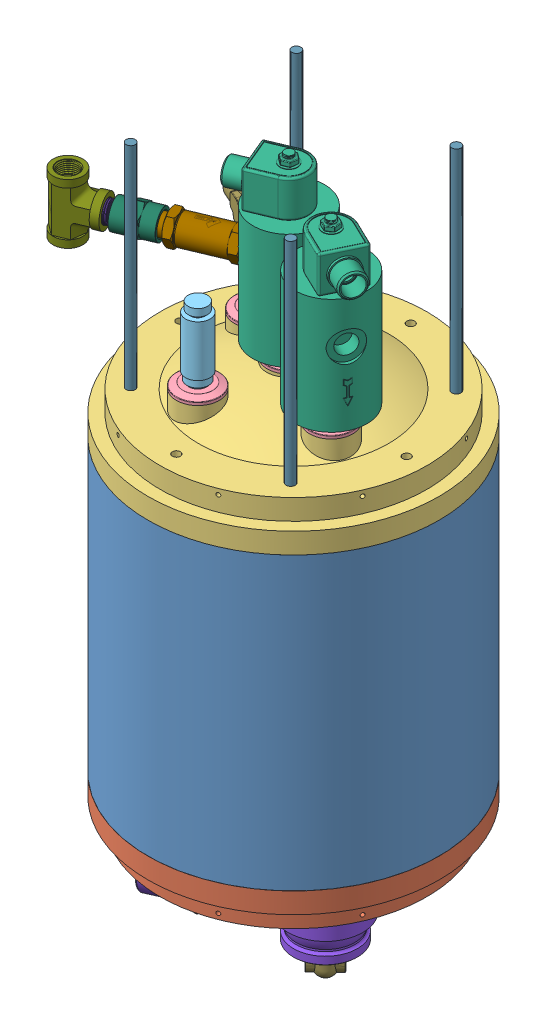
SolidWorks assembly 000053-R02_LOX_TANK_ASSM, configuration Default. Lengths in mm.
Overall size (408.23 765.71 408.23).
29 component instances, 17 part files, 50 mates.
Components (placement in the parent):
- 000055-R02_LOX_TANK_WALL-1: 000055-R02_LOX_TANK_WALL [Default] at (0 -152.4 0) x (0.896707 0 0.442625) z (-0.442625 0 0.896707) size (304.8 304.8 304.8)
- 000052-R02b_TANK_BULKHEAD_BOTTOM-2: 000052-R02b_TANK_BULKHEAD_BOTTOM [Default] at (0 -152.4 0) x (-0.398871 0 0.917007) z (0.917007 0 0.398871) size (304.8 66.04 304.8)
- 000052-R02a_TANK_BULKHEAD_TOP-1: 000052-R02a_TANK_BULKHEAD_TOP [Default] at (0 152.4 0) x (-0.917007 0 -0.398871) z (0.398871 0 -0.917007) size (304.8 66.04 304.8)
- FUELTANKPARTS-1-2-AL-FITTING-3: FUELTANKPARTS-1-2-AL-FITTING [Default] at (-69.8759 209.042 -30.394) x (0.997228 0 0.074408) z (-0.074408 0 0.997228) size (44.96 12.45 44.96)
- FUELTANKPARTS-1-2-AL-FITTING-4: FUELTANKPARTS-1-2-AL-FITTING [Default] at (-8.7345 211.582 -3.7993) x (0.985124 0 -0.171846) z (0.171846 0 0.985124) size (44.96 12.45 44.96)
- FUELTANKPARTS-1-2-AL-FITTING-9: FUELTANKPARTS-1-2-AL-FITTING [Default] at (-30.394 -209.042 69.8759) x (-0.381098 0 -0.924535) z (-0.924535 0 0.381098) size (44.96 12.45 44.96)
- FUELTANKPARTS-1-2-AL-FITTING-10: FUELTANKPARTS-1-2-AL-FITTING [Default] at (10.1313 -211.582 -23.292) x (-0.381098 0 -0.924535) z (-0.924535 0 0.381098) size (44.96 12.45 44.96)
- FUELTANKPARTS-1-2-AL-FITTING-12: FUELTANKPARTS-1-2-AL-FITTING [Default] at (-30.394 209.042 69.8759) x (0.074408 0 -0.997228) z (0.997228 0 0.074408) size (44.96 12.45 44.96)
- FUELTANKPARTS-1-2-AL-FITTING-13: FUELTANKPARTS-1-2-AL-FITTING [Default] at (69.8759 209.042 30.394) x (-0.997228 0 -0.074408) z (0.074408 0 -0.997228) size (44.96 12.45 44.96)
- cryo-pducer-temp-1: cryo-pducer-temp [Default] at (-30.394 211.328 69.8759) size (25.65 83.82 25.65)
- EH50-08-D024-OXXP-1: EH50-08-D024-OXXP [Default] at (-8.7345 311.3278 -3.7993) x (-0.922505 0 0.385985) z (-0.385985 0 -0.922505) size (87.5 168.84 74.93)
- CRVP4-500B-1: CRVP4-500B [Default] at (-69.8759 209.042 -30.394) x (0 1 0) z (0 0 1) size (82.27 25.15 25.15)
- atomatik-2: atomatik [Default] at (10.1313 -265.7517 -23.292) x (0 -1 0) z (-0.405568 0 -0.914065) size (76.23 180.98 78)
- TIN20021-1: TIN20021 [Default] at (-97.1889 311.3278 33.2109) x (0.922505 0 -0.385985) z (-0.385985 0 -0.922505) size (102.11 28.58 33)
- 44665K173_STANDARD-WALL ALUMINUM THREADED PIPE NIPPLE-1: 44665K173_STANDARD-WALL ALUMINUM THREADED PIPE NIPPLE [44665K173] at (69.8759 227.0379 30.394) x (-0.099238 0 -0.995064) z (0 1 0) size (22.19 22.36 51.97)
- 44665K173_STANDARD-WALL ALUMINUM THREADED PIPE NIPPLE-2: 44665K173_STANDARD-WALL ALUMINUM THREADED PIPE NIPPLE [44665K173] at (-8.7345 229.5779 -3.7993) x (0.19121 0 -0.981549) z (0 1 0) size (22.19 22.36 51.97)
- 44665K173_STANDARD-WALL ALUMINUM THREADED PIPE NIPPLE-3: 44665K173_STANDARD-WALL ALUMINUM THREADED PIPE NIPPLE [44665K173] at (10.1313 -229.5779 -23.292) x (-0.147711 0 -0.989031) z (0 1 0) size (22.19 22.36 51.97)
- 48805K184_PRECISION EXTREME-PRESSURE 316SS PIPE FITTING-1: 48805K184_PRECISION EXTREME-PRESSURE 316SS PIPE FITTING [48805K184] at (-30.394 -234.188 69.8759) x (0 -1 0) z (-0.983195 0 -0.182556) size (48.72 34.63 25.66)
- 3861T240_MED-PRESSURE ANODIZED ALUM THRD PIPE FITTING-2: 3861T240_MED-PRESSURE ANODIZED ALUM THRD PIPE FITTING [3861T24] at (-10.4238 -332.3821 -44.8205) x (-0.723269 0 0.690566) z (-0.690566 0 -0.723269) size (30.97 56.51 41.63)
- MCMASTER_94435A523_5in-5: MCMASTER_94435A523_5in [Default] at (-120.6313 -316.23 -2.1217) x (0 1 0) z (-0.995572 0 -0.094007) size (127 9.53 9.53)
- MCMASTER_94435A523_9in-5: MCMASTER_94435A523_9in [Default] at (-86.7995 189.23 83.799) x (0 1 0) z (-0.951783 0 0.306771) size (228.6 9.53 9.53)
- MCMASTER_94435A523_9in-6: MCMASTER_94435A523_9in [Default] at (83.799 189.23 86.7995) x (0 1 0) z (0.306771 0 0.951783) size (228.6 9.53 9.53)
- MCMASTER_94435A523_9in-7: MCMASTER_94435A523_9in [Default] at (86.7995 189.23 -83.799) x (0 1 0) z (0.951783 0 -0.306771) size (228.6 9.53 9.53)
- MCMASTER_94435A523_9in-8: MCMASTER_94435A523_9in [Default] at (-83.799 189.23 -86.7995) x (0 1 0) z (-0.306771 0 -0.951783) size (228.6 9.53 9.53)
- 3861T240_MED-PRESSURE ANODIZED ALUM THRD PIPE FITTING-3: 3861T240_MED-PRESSURE ANODIZED ALUM THRD PIPE FITTING [3861T24] at (-97.0429 312.3406 -42.5575) x (0.408641 0 -0.912695) z (-0.912695 0 -0.408641) size (30.97 56.51 41.63)
- 51205K223_EXTREME-PRESSURE 316 SS THREADED PIPE FITTING-1: 51205K223_EXTREME-PRESSURE 316 SS THREADED PIPE FITTING [51205K223] at (-119.4489 311.3278 42.5247) x (-0.385985 0 -0.922505) z (-0.922505 0 0.385985) size (28.7 32.74 38.1)
- 51205K245_EXTREME-PRESSURE 316 SS THREADED PIPE FITTING-1: 51205K245_EXTREME-PRESSURE 316 SS THREADED PIPE FITTING [51205K245] at (-171.8921 311.3278 64.4675) x (0 -1 0) z (0.385985 0 0.922505) size (63.86 47.51 31.16)
- 44665K211_STANDARD-WALL ALUMINUM THREADED PIPE NIPPLE-1: 44665K211_STANDARD-WALL ALUMINUM THREADED PIPE NIPPLE [44665K211] at (-142.1776 311.3278 52.0346) x (0.36865 0.296317 0.881075) z (-0.922505 0 0.385985) size (21.92 21.87 39.26)
- EH50-08-D024-OXXP-2: EH50-08-D024-OXXP [Default] at (69.8759 308.7878 30.394) x (0.900951 0 0.43392) z (-0.43392 0 0.900951) size (87.5 168.84 74.93)
Mates (geometry in assembly coordinates):
- Coincident1: coincident anti-aligned: line of 000055-R02_LOX_TANK_WALL-1 through (304.8 0 58.4669) axis (0 0 -1); line of 000052-R02a_TANK_BULKHEAD_TOP-1 through (0 102.5587 0) axis (0 1 0)
- Coincident2: coincident aligned: line of 000055-R02_LOX_TANK_WALL-1 through (304.8 0 58.4669) axis (0 0 -1); line of 000052-R02b_TANK_BULKHEAD_BOTTOM-2 through (0 -246.3331 0) axis (0 -1 0)
- Coincident4: coincident anti-aligned: plane of 000055-R02_LOX_TANK_WALL-1 through (0 -246.3331 0) normal (0 -1 0); plane of 000052-R02b_TANK_BULKHEAD_BOTTOM-2 through (-58.2552 -246.3331 133.9289) normal (0 1 0)
- Coincident7: coincident anti-aligned: plane of 000052-R02a_TANK_BULKHEAD_TOP-1 through (-8.7345 218.44 -3.7993) normal (0 1 0); plane of FUELTANKPARTS-1-2-AL-FITTING-4 through (-8.7345 218.44 -3.7993) normal (0 -1 0)
- Coincident9: coincident anti-aligned: plane of 000052-R02b_TANK_BULKHEAD_BOTTOM-2 through (-30.394 -309.8331 69.8759) normal (0 -1 0); plane of FUELTANKPARTS-1-2-AL-FITTING-9 through (-30.394 -309.8331 69.8759) normal (0 1 0)
- Concentric8: concentric anti-aligned: cylinder of 000052-R02b_TANK_BULKHEAD_BOTTOM-2 through (-30.394 -309.8331 69.8759) axis (0 -1 0) radius 12.7; cylinder of FUELTANKPARTS-1-2-AL-FITTING-9 through (-30.394 -309.8331 69.8759) axis (0 1 0) radius 12.7
- Coincident10: coincident anti-aligned: plane of 000052-R02b_TANK_BULKHEAD_BOTTOM-2 through (10.1313 -312.3731 -23.292) normal (0 -1 0); plane of FUELTANKPARTS-1-2-AL-FITTING-10 through (10.1313 -312.3731 -23.292) normal (0 1 0)
- Concentric9: concentric anti-aligned: cylinder of 000052-R02b_TANK_BULKHEAD_BOTTOM-2 through (10.1313 -312.3731 -23.292) axis (0 -1 0) radius 12.7; cylinder of FUELTANKPARTS-1-2-AL-FITTING-10 through (10.1313 -312.3731 -23.292) axis (0 1 0) radius 12.7
- Concentric10: concentric anti-aligned: cylinder of 000052-R02a_TANK_BULKHEAD_TOP-1 through (-69.8759 215.9 -30.394) axis (0 1 0) radius 12.7; cylinder of FUELTANKPARTS-1-2-AL-FITTING-3 through (-69.8759 215.9 -30.394) axis (0 -1 0) radius 12.7
- Coincident13: coincident anti-aligned: plane of 000052-R02a_TANK_BULKHEAD_TOP-1 through (-69.8759 215.9 -30.394) normal (0 1 0); plane of FUELTANKPARTS-1-2-AL-FITTING-3 through (-69.8759 215.9 -30.394) normal (0 -1 0)
- Concentric12: concentric anti-aligned: cylinder of FUELTANKPARTS-1-2-AL-FITTING-9 through (-30.394 -315.4211 69.8759) axis (0 1 0) radius 9.271; cylinder of FUELTANKPARTS-1-2-AL-FITTING-12 through (-30.394 221.488 69.8759) axis (0 -1 0) radius 9.271
- Concentric13: concentric aligned: cylinder of FUELTANKPARTS-1-2-AL-FITTING-12 through (-30.394 221.488 69.8759) axis (0 -1 0) radius 9.271; cylinder of cryo-pducer-temp-1 through (-30.394 211.328 69.8759) axis (0 -1 0) radius 8.89
- Distance2: distance = 2.54 mm anti-aligned: plane of cryo-pducer-temp-1 through (-18.964 224.028 69.8759) normal (0 -1 0); plane of FUELTANKPARTS-1-2-AL-FITTING-12 through (-30.394 221.488 69.8759) normal (0 1 0)
- Concentric14: concentric anti-aligned: cylinder of FUELTANKPARTS-1-2-AL-FITTING-4 through (-8.7345 224.028 -3.7993) axis (0 -1 0) radius 9.271; cone of EH50-08-D024-OXXP-1 through (-8.7345 235.1278 -3.7993) axis (0 1 0)
- Concentric16: concentric anti-aligned: cylinder of 000052-R02a_TANK_BULKHEAD_TOP-1 through (-8.7345 218.44 -3.7993) axis (0 1 0) radius 12.7; cylinder of FUELTANKPARTS-1-2-AL-FITTING-4 through (-8.7345 218.44 -3.7993) axis (0 -1 0) radius 12.7
- Concentric19: concentric aligned: cylinder of FUELTANKPARTS-1-2-AL-FITTING-3 through (-69.8759 221.488 -30.394) axis (0 -1 0) radius 9.271; cone of CRVP4-500B-1 through (-69.8759 224.028 -30.394) axis (0 -1 0)
- Distance5: distance = 2.54 mm anti-aligned: plane of CRVP4-500B-1 through (-69.8759 224.028 -30.394) normal (0 -1 0); plane of FUELTANKPARTS-1-2-AL-FITTING-3 through (-69.8759 221.488 -30.394) normal (0 1 0)
- Concentric22: concentric aligned: cone of EH50-08-D024-OXXP-1 through (-40.0157 311.3278 9.2891) axis (0.922505 0 -0.385985); cone of TIN20021-1 through (-38.6977 311.3278 8.7376) axis (0.922505 0 -0.385985)
- Coincident26: coincident anti-aligned: plane of EH50-08-D024-OXXP-1; plane of TIN20021-1
- Concentric32: concentric anti-aligned: cylinder of FUELTANKPARTS-1-2-AL-FITTING-13 through (69.8759 221.488 30.394) axis (0 -1 0) radius 9.271; cylinder of 44665K173_STANDARD-WALL ALUMINUM THREADED PIPE NIPPLE-1 through (69.8759 221.488 30.394) axis (0 1 0) radius 10.668
- Coincident35: coincident aligned: plane of FUELTANKPARTS-1-2-AL-FITTING-13 through (69.8759 221.488 30.394) normal (0 1 0); circle of 44665K173_STANDARD-WALL ALUMINUM THREADED PIPE NIPPLE-1
- Concentric34: concentric anti-aligned: cylinder of FUELTANKPARTS-1-2-AL-FITTING-4 through (-8.7345 224.028 -3.7993) axis (0 -1 0) radius 9.271; cylinder of 44665K173_STANDARD-WALL ALUMINUM THREADED PIPE NIPPLE-2 through (-8.7345 224.028 -3.7993) axis (0 1 0) radius 10.668
- Coincident37: coincident aligned: plane of EH50-08-D024-OXXP-1 through (-11.6634 235.1278 -2.5737) normal (0 -1 0); circle of 44665K173_STANDARD-WALL ALUMINUM THREADED PIPE NIPPLE-2
- Coincident38: coincident aligned: plane of FUELTANKPARTS-1-2-AL-FITTING-4 through (-8.7345 224.028 -3.7993) normal (0 1 0); circle of 44665K173_STANDARD-WALL ALUMINUM THREADED PIPE NIPPLE-2
- Concentric35: concentric aligned: cylinder of atomatik-2 through (10.1313 -384.3156 -23.292) axis (0 1 0) radius 16.775; cylinder of 44665K173_STANDARD-WALL ALUMINUM THREADED PIPE NIPPLE-3 through (10.1313 -329.0609 -23.292) axis (0 1 0) radius 10.668
- Concentric36: concentric aligned: cylinder of FUELTANKPARTS-1-2-AL-FITTING-10 through (10.1313 -317.9611 -23.292) axis (0 1 0) radius 9.271; cylinder of 44665K173_STANDARD-WALL ALUMINUM THREADED PIPE NIPPLE-3 through (10.1313 -329.0609 -23.292) axis (0 1 0) radius 10.668
- Coincident39: coincident aligned: plane of FUELTANKPARTS-1-2-AL-FITTING-10 through (10.1313 -317.9611 -23.292) normal (0 -1 0); circle of 44665K173_STANDARD-WALL ALUMINUM THREADED PIPE NIPPLE-3
- Coincident40: coincident aligned: plane of atomatik-2 through (25.4648 -329.0609 -30.0954) normal (0 1 0); circle of 44665K173_STANDARD-WALL ALUMINUM THREADED PIPE NIPPLE-3
- Concentric37: concentric aligned: cylinder of FUELTANKPARTS-1-2-AL-FITTING-9 through (-30.394 -315.4211 69.8759) axis (0 1 0) radius 9.271; cylinder of 48805K184_PRECISION EXTREME-PRESSURE 316SS PIPE FITTING-1 through (-30.394 -328.1211 69.8759) axis (0 1 0) radius 5.207
- Coincident41: coincident anti-aligned: plane of FUELTANKPARTS-1-2-AL-FITTING-9 through (-30.394 -315.4211 69.8759) normal (0 -1 0); plane of 48805K184_PRECISION EXTREME-PRESSURE 316SS PIPE FITTING-1 through (-52.2455 -315.4211 65.8186) normal (0 1 0)
- Concentric38: concentric aligned: cylinder of atomatik-2 through (10.1313 -384.3156 -23.292) axis (0 1 0) radius 16.775; cylinder of 3861T240_MED-PRESSURE ANODIZED ALUM THRD PIPE FITTING-2 through (10.1313 -408.4558 -23.292) axis (0 1 0) radius 6.7469
- Coincident42: coincident anti-aligned: plane of atomatik-2 through (31.2691 -405.2872 -32.6707) normal (0 -1 0); plane of 3861T240_MED-PRESSURE ANODIZED ALUM THRD PIPE FITTING-2 through (33.3722 -405.2872 -20.7894) normal (0 1 0)
- Concentric43: concentric aligned: cylinder of 000052-R02b_TANK_BULKHEAD_BOTTOM-2 through (-120.6313 -289.5131 -2.1217) axis (0 -1 0) radius 4.2164; cylinder of MCMASTER_94435A523_5in-5 through (-120.6313 -283.1631 -2.1217) axis (0 -1 0) radius 4.7625
- Distance7: distance = 6.35 mm anti-aligned: plane of MCMASTER_94435A523_5in-5 through (-120.6313 -189.23 -2.1217) normal (0 1 0); plane of 000052-R02b_TANK_BULKHEAD_BOTTOM-2 through (-55.7223 -195.58 128.1059) normal (0 -1 0)
- Concentric45: concentric anti-aligned: cylinder of 000052-R02a_TANK_BULKHEAD_TOP-1 through (-86.7995 195.58 83.799) axis (0 1 0) radius 4.2164; cylinder of MCMASTER_94435A523_9in-5 through (-86.7995 417.83 83.799) axis (0 -1 0) radius 4.7625
- Distance8: distance = 6.35 mm anti-aligned: plane of MCMASTER_94435A523_9in-5 through (-86.7995 189.23 83.799) normal (0 -1 0); plane of 000052-R02a_TANK_BULKHEAD_TOP-1 through (-128.1059 195.58 -55.7223) normal (0 1 0)
- Concentric46: concentric anti-aligned: cylinder of CRVP4-500B-1 through (-69.8759 262.382 -30.394) axis (0 1 0) radius 7.9375; cylinder of 3861T240_MED-PRESSURE ANODIZED ALUM THRD PIPE FITTING-3 through (-69.8759 294.4813 -30.394) axis (0 -1 0) radius 6.7469
- Coincident49: coincident anti-aligned: plane of CRVP4-500B-1 through (-69.8759 291.3126 -30.394) normal (0 1 0); plane of 3861T240_MED-PRESSURE ANODIZED ALUM THRD PIPE FITTING-3 through (-59.7386 291.3126 -9.3313) normal (0 -1 0)
- Concentric48: concentric aligned: cone of TIN20021-1 through (-98.5069 311.3278 33.7624) axis (-0.922505 0 0.385985); cylinder of 51205K223_EXTREME-PRESSURE 316 SS THREADED PIPE FITTING-1 through (-137.0227 311.3278 49.8778) axis (-0.922505 0 0.385985) radius 6.35
- Distance9: distance = 5.08 mm anti-aligned: plane of TIN20021-1 through (-94.0049 311.3278 40.8206) normal (-0.922505 0 0.385985); plane of 51205K223_EXTREME-PRESSURE 316 SS THREADED PIPE FITTING-1 through (-101.8752 311.3278 35.1717) normal (0.922505 0 -0.385985)
- Parallel2: parallel aligned: plane of 000052-R02a_TANK_BULKHEAD_TOP-1 through (-128.1059 195.58 -55.7223) normal (0 1 0); plane of TIN20021-1 through (-44.4677 325.6153 11.1519) normal (0 1 0)
- Angle2: planar angle = 0.523599 rad anti-aligned: plane of 51205K223_EXTREME-PRESSURE 316 SS THREADED PIPE FITTING-1 through (-74.0275 294.83 23.52) normal (0.192993 -0.866025 0.461253); plane of TIN20021-1 through (-93.2055 325.6153 31.5442) normal (0 1 0)
- Parallel3: parallel aligned: plane of 51205K223_EXTREME-PRESSURE 316 SS THREADED PIPE FITTING-1 through (-79.5423 319.5767 10.3397) normal (-0.385985 0 -0.922505); plane of 51205K245_EXTREME-PRESSURE 316 SS THREADED PIPE FITTING-1 through (-166.2926 299.6121 47.4973) normal (-0.385985 0 -0.922505)
- Concentric54: concentric anti-aligned: cylinder of 51205K223_EXTREME-PRESSURE 316 SS THREADED PIPE FITTING-1 through (-137.0227 311.3278 49.8778) axis (-0.922505 0 0.385985) radius 6.35; cylinder of 44665K211_STANDARD-WALL ALUMINUM THREADED PIPE NIPPLE-1 through (-160.293 311.3278 59.6143) axis (0.922505 0 -0.385985) radius 7.8994
- Concentric55: concentric anti-aligned: cylinder of 51205K245_EXTREME-PRESSURE 316 SS THREADED PIPE FITTING-1 through (-155.4899 311.3278 57.6046) axis (-0.922505 0 0.385985) radius 8.001; cylinder of 44665K211_STANDARD-WALL ALUMINUM THREADED PIPE NIPPLE-1 through (-160.293 311.3278 59.6143) axis (0.922505 0 -0.385985) radius 7.8994
- Coincident58: coincident anti-aligned: circle of 51205K223_EXTREME-PRESSURE 316 SS THREADED PIPE FITTING-1; plane of 44665K211_STANDARD-WALL ALUMINUM THREADED PIPE NIPPLE-1 through (-124.6039 311.3278 44.6816) normal (0.922505 0 -0.385985)
- Coincident59: coincident aligned: circle of 51205K245_EXTREME-PRESSURE 316 SS THREADED PIPE FITTING-1; plane of 44665K211_STANDARD-WALL ALUMINUM THREADED PIPE NIPPLE-1 through (-159.7513 311.3278 59.3877) normal (-0.922505 0 0.385985)
- Concentric56: concentric aligned: cylinder of 44665K173_STANDARD-WALL ALUMINUM THREADED PIPE NIPPLE-1 through (69.8759 221.488 30.394) axis (0 1 0) radius 10.668; cone of EH50-08-D024-OXXP-2 through (69.8759 232.5878 30.394) axis (0 1 0)
- Coincident60: coincident anti-aligned: circle of 44665K173_STANDARD-WALL ALUMINUM THREADED PIPE NIPPLE-1; plane of EH50-08-D024-OXXP-2 through (72.7364 232.5878 31.7717) normal (0 -1 0)
- Coincident61: coincident anti-aligned: plane of 000055-R02_LOX_TANK_WALL-1 through (0 152.4 0) normal (0 1 0); plane of 000052-R02a_TANK_BULKHEAD_TOP-1 through (-133.9289 152.4 -58.2552) normal (0 -1 0)
